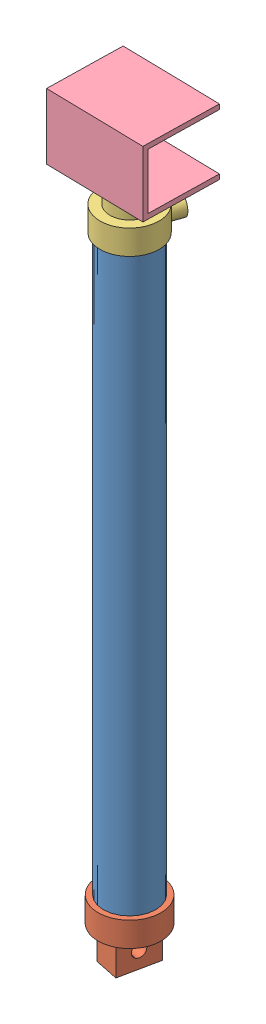
SolidWorks assembly Assem1, configuration Default. Lengths in mm.
Overall size (60.91 456 52.63).
5 component instances, 5 part files, 6 mates.
Components (placement in the parent):
- cylender p1-1: cylender p1 [Default] at (-29.2356 -110.6399 340.4393) size (32 350 32)
- end part p 1-1: end part p 1 [Default] at (-29.2356 -125.6399 340.4393) x (-0.979079 0 -0.203481) z (-0.203481 0 0.979079) size (38.33 39 38.33)
- start point-1: start point [Default] at (-29.2356 239.3601 340.4393) x (0.337553 0 -0.941307) z (-0.941307 0 -0.337553) size (43 33 36)
- Part7^Assem1-1: Part7^Assem1 [Default] at origin (virtual)
- PISTON'-1: PISTON' [Default] at (-29.2356 -82.6399 340.4393) x (0.999798 0 0.020101) z (0.020101 0 -0.999798) size (60 397 45.81)
Mates (geometry in assembly coordinates):
- Concentric2: concentric: cylinder of cylender p1-1 through (-29.2356 239.3601 340.4393) axis (0 -1 0) radius 16; cylinder of end part p 1-1 through (-29.2356 -110.6399 340.4393) axis (0 -1 0) radius 19.165
- Coincident1: coincident: plane of cylender p1-1 through (-29.2356 -110.6399 340.4393) normal (0 -1 0); plane of end part p 1-1 through (-29.2356 -110.6399 340.4393) normal (0 1 0)
- Coincident2: coincident: plane of cylender p1-1 through (-29.2356 239.3601 340.4393) normal (0 1 0); plane of start point-1 through (-29.2356 239.3601 340.4393) normal (0 -1 0)
- Concentric3: concentric: cylinder of cylender p1-1 through (-29.2356 239.3601 340.4393) axis (0 -1 0) radius 16; cylinder of start point-1 through (-29.2356 254.3601 340.4393) axis (0 -1 0) radius 18
- Concentric4: concentric: cylinder of cylender p1-1 through (-29.2356 239.3601 340.4393) axis (0 -1 0) radius 16; cylinder of PISTON'-1 through (-29.2356 270.3601 340.4393) axis (0 -1 0) radius 5
- LimitDistance1: limit distance = 20 mm: plane of PISTON'-1 through (-29.2356 -86.6399 340.4393) normal (0 -1 0); plane of end part p 1-1 through (-29.2356 -106.6399 340.4393) normal (0 1 0)
